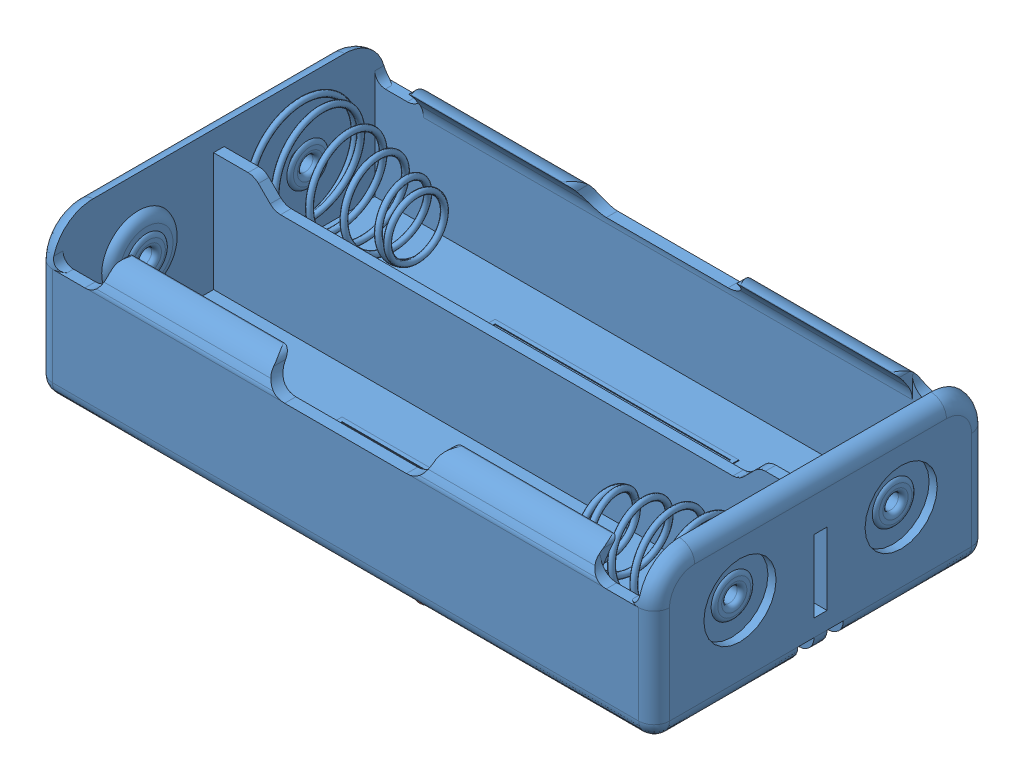
SolidWorks assembly Assembly batterijhouder, configuration Default. Lengths in mm.
Overall size (76 27.1 41.1).
4 component instances, 3 part files, 11 mates.
Components (placement in the parent):
- Batterijhouder 2 x 18650-1: Batterijhouder 2 x 18650 [Default] x (1 0 0) z (0 1 0) size (76 41.1 19)
- Batterij 2 x 18650-1: Batterij 2 x 18650 [Default] x (1 0 0) z (0 1 0) size (69.6 38.05 18.2) (hidden)
- countersunk flat head cross recess screw_iso-2: countersunk flat head cross recess screw_iso [ISO 7046-1 - M3 x 10 - Z - 10N] at (0 1.9 -9.925) x (0 -1 0) z (0 0 1) size (10 5.5 5.5)
- countersunk flat head cross recess screw_iso-3: countersunk flat head cross recess screw_iso [ISO 7046-1 - M3 x 10 - Z - 10N] at (0 1.9 9.925) x (0 -1 0) z (-1 0 0) size (10 5.5 5.5)
Mates (geometry in assembly coordinates):
- Coincident1: coincident aligned: plane of Battery holder 2 x 18650-1 through (0 0 0) normal (1 0 0)
- Coincident2: coincident aligned: plane of Battery holder 2 x 18650-1 through (0 0 0) normal (0 1 0)
- Coincident3: coincident anti-aligned: plane of Battery holder 2 x 18650-1 through (0 0 0) normal (0 0 -1)
- Coincident4: coincident aligned: plane of Battery 2 x 18650-1 through (0 0 0) normal (1 0 0)
- Coincident5: coincident anti-aligned: plane of Battery 2 x 18650-1 through (0 0 0) normal (0 0 -1)
- Coincident6: coincident aligned: plane of assembly through (0 0 0) normal (0 1 0); plane of ? through (0 0 0) normal (0 1 0)
- Coincident7: coincident aligned: plane of countersunk flat head cross recess screw_iso-2 through (0 1.9 -9.925) normal (0 1 0); plane of countersunk flat head cross recess screw_iso-3 through (0 1.9 9.925) normal (0 1 0)
- Concentric1: concentric aligned: cylinder of Battery holder 2 x 18650-1 through (0 -86.5526 9.925) axis (0 1 0) radius 1.55; cylinder of countersunk flat head cross recess screw_iso-3 through (0 8.25 9.925) axis (0 1 0) radius 1.5
- Concentric2: concentric aligned: cylinder of Battery holder 2 x 18650-1 through (0 -86.5526 -9.925) axis (0 1 0) radius 1.55; cylinder of countersunk flat head cross recess screw_iso-2 through (0 8.25 -9.925) axis (0 1 0) radius 1.5
- Coincident8: coincident aligned: plane of countersunk flat head cross recess screw_iso-2 through (-0.37 -0.11 -10.4229) normal (1 0 0); plane of countersunk flat head cross recess screw_iso-3 through (-0.37 -0.11 9.4271) normal (1 0 0)
- Coincident9: coincident aligned: plane of Battery holder 2 x 18650-1 through (0 1.9 0) normal (0 1 0); plane of countersunk flat head cross recess screw_iso-2 through (0 1.9 -9.925) normal (0 1 0)
